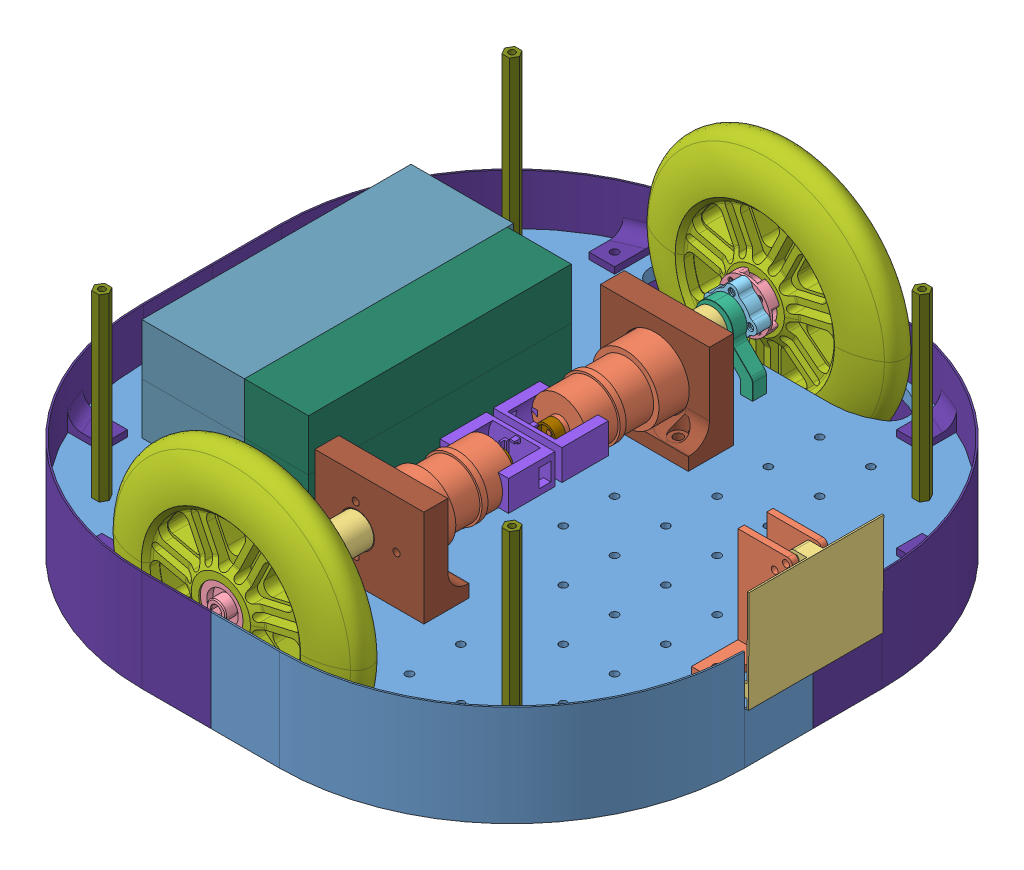
SolidWorks assembly BasePlateAssembly, configuration Default. Lengths in mm.
Overall size (300.06 127.13 298.45).
46 component instances, 22 part files, 59 mates.
Components (placement in the parent):
- BasePlate-1: BasePlate [Default] at (0 276.6946 0) size (296.86 6.35 296.86)
- DriveBase-1: DriveBase [Default] at (21.7349 245.9728 -86.9216) size (124.46 124.46 293.2)
  - DriveAssemblyLeft-1: DriveAssemblyLeft [Default] at (-13.1108 55.1108 149.3123) size (124.46 124.46 144.88)
    - 1400-0032-0032 assembly.STEP-1: 1400-0032-0032 assembly.STEP [Default] at (6.581 -3.5947 -1.114) size (42.17 43 8) (hidden)
    - Motor-2: Motor [Default] at (-2.6241 5.961 7.9343) x (0 0 -1) z (0 1 0) size (70.6 33 33)
    - Coupler-1: Coupler [Default] at (-8.6241 5.961 25.3343) x (0 0 1) z (-0.88407 -0.467355 0) size (22.5 16 16)
    - 595630 assembly.STEP-1: 595630 assembly.STEP [Default] at (-50.3353 -14.4315 51.5475) x (-0.997959 -0.063851 0) z (-0.063851 0.997959 0) size (25.39 31.39 25.39)
    - 545579 assembly.STEP-1: 545579 assembly.STEP [Default] at (19.7418 -41.3992 66.5368) x (0.750814 -0.660514 0) z (0.660514 0.750814 0) size (20.57 9.61 20.57)
    - 1602-0032-0250 assembly.STEP-1: 1602-0032-0250 assembly.STEP [Default] at (-40.6325 25.9608 25.7882) x (-1 0 0) z (0 -1 0) size (38 7 33.35)
    - 3608-0001-0125 assembly.STEP-1: 3608-0001-0125 assembly.STEP [Default] at (-21.1121 15.7426 69.8072) size (124.46 124.46 23.93)
    - Encoder_BracketMount_V2-1: Encoder_BracketMount_V2 [Default] at (-2.6241 5.961 -58.6657) x (0 1 0) z (0 0 1) size (15 34 23)
    - Encoder_MagnetMount_V2-1: Encoder_MagnetMount_V2 [Default] at (-2.6241 5.961 -49.8657) x (-1 0 0) z (0 0 -1) size (10 10 5)
    - 634060-1: 634060 [Default] at (-8.6241 5.961 55.6343) x (0 -1 0) z (1 0 0) size (5.71 25.4 6.34)
    - MotorMount-1: MotorMount [Default] at (-2.6241 5.961 11.1093) size (54 48 23.2)
  - DriveAssemblyRight-1: DriveAssemblyRight [Default] at (-18.359 55.1108 24.531) x (-1 0 0) z (0 0 -1) size (124.46 124.46 144.88)
    - 1400-0032-0032 assembly.STEP-1: 1400-0032-0032 assembly.STEP [Default] at (6.581 -3.5947 -1.114) size (42.17 43 8) (hidden)
    - Motor-2: Motor [Default] at (-2.6241 5.961 7.9343) x (0 0 -1) z (0 -1 0) size (70.6 33 33)
    - Coupler-1: Coupler [Default] at (3.3759 5.961 25.3343) x (0 0 1) z (-0.88407 -0.467355 0) size (22.5 16 16)
    - 595630 assembly.STEP-1: 595630 assembly.STEP [Default] at (-38.3353 -14.4315 51.5475) x (-0.997959 -0.063851 0) z (-0.063851 0.997959 0) size (25.39 31.39 25.39)
    - 545579 assembly.STEP-1: 545579 assembly.STEP [Default] at (31.7418 -41.3992 66.5368) x (0.750814 -0.660514 0) z (0.660514 0.750814 0) size (20.57 9.61 20.57)
    - 1602-0032-0250 assembly.STEP-1: 1602-0032-0250 assembly.STEP [Default] at (-28.6325 25.9608 25.7882) x (-1 0 0) z (0 -1 0) size (38 7 33.35)
    - 3608-0001-0125 assembly.STEP-1: 3608-0001-0125 assembly.STEP [Default] at (-9.1121 15.7426 69.8072) size (124.46 124.46 23.93)
    - Encoder_BracketMount_V2-1: Encoder_BracketMount_V2 [Default] at (-2.6241 5.961 -58.6657) x (0 1 0) z (0 0 1) size (15 34 23)
    - Encoder_MagnetMount_V2-1: Encoder_MagnetMount_V2 [Default] at (-2.6241 5.961 -49.8657) x (-1 0 0) z (0 0 -1) size (10 10 5)
    - 634060-1: 634060 [Default] at (3.3759 5.961 55.6343) x (0 -1 0) z (1 0 0) size (5.71 25.4 6.34)
    - MotorMount-1: MotorMount [Default] at (-2.6241 5.961 11.1093) size (54 48 23.2)
- pololu-ball-caster-with-0-750in-metal-ball.step-1: pololu-ball-caster-with-0-750in-metal-ball.step [Default] at (-127 266.2445 0) x (0 0 -1) z (-1 0 0) size (22.87 20.95 22.86)
- pololu-ball-caster-with-0-750in-metal-ball.step-2: pololu-ball-caster-with-0-750in-metal-ball.step [Default] at (127 266.2445 0) x (-0.088505 0 -0.996076) z (-0.996076 0 0.088505) size (22.87 20.95 22.86)
- CasterMount-1: CasterMount [Default] at (127 272.023 0) x (-1 0 0) z (0 0 1) size (22.86 10.45 63.5)
- CasterMount-2: CasterMount [Default] at (-127 272.023 0) x (-1 0 0) z (0 0 1) size (22.86 10.45 63.5)
- NiMH Battery-2: NiMH Battery [Default] at (-91.2812 308.4446 0) x (0 0 -1) z (1 0 0) size (133.35 25.4 50.8)
- NiMH Battery-3: NiMH Battery [Default] at (-91.2812 283.0446 0) x (0 0 -1) z (1 0 0) size (133.35 25.4 50.8)
- 5V Battery-2: 5V Battery [Default] at (-50.0063 283.0446 1.5875) x (0 0 -1) z (1 0 0) size (130.18 25.4 31.75)
- 5V Battery-3: 5V Battery [Default] at (-50.0063 308.4446 1.5875) x (0 0 -1) z (1 0 0) size (130.18 25.4 31.75)
- Standoff-1: Standoff [Default] at (101.6 283.0446 -101.6) size (7.33 88.9 6.35)
- Standoff-2: Standoff [Default] at (101.6 283.0446 101.6) size (7.33 88.9 6.35)
- Standoff-3: Standoff [Default] at (-101.6 283.0446 101.6) size (7.33 88.9 6.35)
- Standoff-4: Standoff [Default] at (-101.6 283.0446 -101.6) size (7.33 88.9 6.35)
- BumperMountsV2-1: BumperMountsV2 [Default] at (0 276.6946 0) size (149.22 50 149.22)
- tapesensormount-1: tapesensormount [Default] at (6 274.1946 60.325) size (44.45 25.15 14.08)
- tapesensormount-2: tapesensormount [Default] at (6 274.1946 -60.325) x (-1 0 0) z (0 0 -1) size (44.45 25.15 14.08)
- BumperMountsV2-2: BumperMountsV2 [Default] at (0 276.6946 0) x (0 0 -1) z (1 0 0) size (149.22 50 149.22)
- BumperMountsLimitV2-1: BumperMountsLimitV2 [Default] at (0 276.6946 0) x (-1 0 0) z (0 0 -1) size (149.22 50 149.22)
- BumperMountsV2-3: BumperMountsV2 [Default] at (0 276.6946 0) x (0 0 1) z (-1 0 0) size (149.22 50 149.22)
- limitswitchmount-1: limitswitchmount [Default] at (127 283.0446 0) x (0 0 1) z (-1 0 0) size (63.5 50.8 27.78)
- limitplate-1: limitplate [Default] at (149.8442 308.4017 0) x (0 0 -1) z (0.999969 -0.007846 0) size (66.67 50.8 9.52)
Mates (geometry in assembly coordinates):
- Coincident1: coincident anti-aligned: plane of BasePlate-1 through (-34.1313 283.0446 34.1313) normal (0 1 0); plane of DriveBase-1/DriveAssemblyRight-1/1400-0032-0032 assembly.STEP-1 through (-7 283.0446 -64.325) normal (0 -1 0)
- Symmetric1: symmetric: plane of BasePlate-1 through (0 276.6946 0) normal (0 0 1); plane of DriveBase-1/DriveAssemblyLeft-1/1400-0032-0032 assembly.STEP-1 through (6 307.0446 -56.325) normal (0 0 1); plane of DriveBase-1/DriveAssemblyRight-1/1400-0032-0032 assembly.STEP-1 through (6 307.0446 56.325) normal (0 0 -1)
- Symmetric2: symmetric aligned: plane of BasePlate-1 through (0 276.6946 0) normal (1 0 0); plane of DriveBase-1/DriveAssemblyLeft-1/1602-0032-0250 assembly.STEP-1 through (-19 292.2872 100.1875) normal (-1 0 0); plane of DriveBase-1/DriveAssemblyLeft-1/1602-0032-0250 assembly.STEP-1 through (19 292.2872 100.1875) normal (1 0 0)
- Concentric4: concentric anti-aligned: cylinder of pololu-ball-caster-with-0-750in-metal-ball.step-2 through (127 262.4345 0) axis (0 -1 0) radius 11.43; cylinder of CasterMount-1 through (127 266.2445 0) axis (0 1 0) radius 11.43
- Coincident5: coincident anti-aligned: plane of pololu-ball-caster-with-0-750in-metal-ball.step-2 through (127 266.2445 0) normal (0 1 0); plane of CasterMount-1 through (127 266.2445 0) normal (0 -1 0)
- Concentric8: concentric anti-aligned: cylinder of pololu-ball-caster-with-0-750in-metal-ball.step-1 through (-127 262.4345 0) axis (0 -1 0) radius 11.43; cylinder of CasterMount-2 through (-127 266.2445 0) axis (0 1 0) radius 11.43
- Coincident6: coincident anti-aligned: plane of pololu-ball-caster-with-0-750in-metal-ball.step-1 through (-127 266.2445 0) normal (0 1 0); plane of CasterMount-2 through (-127 266.2445 0) normal (0 -1 0)
- Coincident12: coincident aligned: plane of BasePlate-1 through (0 276.6946 0) normal (0 0 1)
- Coincident14: coincident aligned: plane of BasePlate-1 through (0 276.6946 0) normal (1 0 0)
- Coincident16: coincident anti-aligned: plane of NiMH Battery-2 through (-91.2812 308.4446 0) normal (0 -1 0); plane of NiMH Battery-3 through (-91.2812 308.4446 0) normal (0 1 0)
- Coincident17: coincident aligned: plane of NiMH Battery-2 through (-65.8813 333.8446 66.675) normal (1 0 0); plane of NiMH Battery-3 through (-65.8813 308.4446 66.675) normal (1 0 0)
- Coincident18: coincident aligned: plane of NiMH Battery-2 through (-65.8813 333.8446 66.675) normal (0 0 1); plane of NiMH Battery-3 through (-65.8813 308.4446 66.675) normal (0 0 1)
- Coincident19: coincident aligned: plane of NiMH Battery-2 through (-65.8813 333.8446 66.675) normal (0 0 1); plane of 5V Battery-3 through (-34.1313 333.8446 66.675) normal (0 0 1)
- Coincident20: coincident aligned: plane of NiMH Battery-2 through (-91.2812 333.8446 0) normal (0 1 0); plane of 5V Battery-3 through (-50.0063 333.8446 1.5875) normal (0 1 0)
- Coincident21: coincident anti-aligned: plane of 5V Battery-2 through (-50.0063 308.4446 1.5875) normal (0 1 0); plane of 5V Battery-3 through (-50.0063 308.4446 1.5875) normal (0 -1 0)
- Coincident22: coincident anti-aligned: plane of NiMH Battery-3 through (-65.8813 308.4446 66.675) normal (1 0 0); plane of 5V Battery-2 through (-65.8813 308.4446 66.675) normal (-1 0 0)
- Coincident23: coincident aligned: plane of 5V Battery-2 through (-34.1313 308.4446 66.675) normal (1 0 0); plane of 5V Battery-3 through (-34.1313 333.8446 66.675) normal (1 0 0)
- Coincident24: coincident aligned: plane of NiMH Battery-3 through (-65.8813 308.4446 66.675) normal (0 0 1); plane of 5V Battery-3 through (-34.1313 333.8446 66.675) normal (0 0 1)
- Coincident25: coincident aligned: plane of 5V Battery-2 through (-34.1313 308.4446 66.675) normal (0 0 1); plane of 5V Battery-3 through (-34.1313 333.8446 66.675) normal (0 0 1)
- Coincident26: coincident anti-aligned: plane of BasePlate-1 through (-34.1313 283.0446 34.1313) normal (0 1 0); plane of NiMH Battery-3 through (-91.2812 283.0446 0) normal (0 -1 0)
- Width1: width aligned: plane of NiMH Battery-2 through (-65.8813 333.8446 66.675) normal (0 0 1); plane of NiMH Battery-2 through (-65.8813 333.8446 -66.675) normal (0 0 -1); plane of BasePlate-1 through (-34.1313 283.0446 148.4312) normal (0 0 1); plane of BasePlate-1 through (-34.1313 283.0446 -148.4312) normal (0 0 -1)
- Distance4: distance = 31.75 mm aligned: plane of NiMH Battery-3 through (-116.6813 308.4446 66.675) normal (-1 0 0); plane of BasePlate-1 through (-148.4312 283.0446 34.1313) normal (-1 0 0)
- Concentric13: concentric aligned: cylinder of BasePlate-1 through (127 283.0446 25.4) axis (0 1 0) radius 1.8986; cylinder of CasterMount-1 through (127 276.6946 25.4) axis (0 1 0) radius 1.8986
- Concentric14: concentric aligned: cylinder of BasePlate-1 through (127 283.0446 -25.4) axis (0 1 0) radius 1.8986; cylinder of CasterMount-1 through (127 276.6946 -25.4) axis (0 1 0) radius 1.8986
- Concentric15: concentric aligned: cylinder of BasePlate-1 through (-127 283.0446 25.4) axis (0 1 0) radius 1.8986; cylinder of CasterMount-2 through (-127 276.6946 25.4) axis (0 1 0) radius 1.8986
- Concentric16: concentric aligned: cylinder of BasePlate-1 through (-127 283.0446 -25.4) axis (0 1 0) radius 1.8986; cylinder of CasterMount-2 through (-127 276.6946 -25.4) axis (0 1 0) radius 1.8986
- Coincident36: coincident anti-aligned: plane of BasePlate-1 through (-34.1313 276.6946 34.1313) normal (0 -1 0); plane of CasterMount-1 through (127 276.6946 0) normal (0 1 0)
- Coincident37: coincident anti-aligned: plane of BasePlate-1 through (-34.1313 276.6946 34.1313) normal (0 -1 0); plane of CasterMount-2 through (-127 276.6946 0) normal (0 1 0)
- Concentric21: concentric anti-aligned: cylinder of Standoff-1 through (101.6 371.9446 -101.6) axis (0 -1 0) radius 1.5875; cylinder of BasePlate-1 through (101.6 283.0446 -101.6) axis (0 1 0) radius 1.8986
- Concentric22: concentric anti-aligned: cylinder of BasePlate-1 through (101.6 283.0446 101.6) axis (0 1 0) radius 1.8986; cylinder of Standoff-2 through (101.6 371.9446 101.6) axis (0 -1 0) radius 1.5875
- Concentric23: concentric anti-aligned: cylinder of BasePlate-1 through (-101.6 283.0446 101.6) axis (0 1 0) radius 1.8986; cylinder of Standoff-3 through (-101.6 371.9446 101.6) axis (0 -1 0) radius 1.5875
- Concentric24: concentric anti-aligned: cylinder of BasePlate-1 through (-101.6 283.0446 -101.6) axis (0 1 0) radius 1.8986; cylinder of Standoff-4 through (-101.6 371.9446 -101.6) axis (0 -1 0) radius 1.5875
- Coincident40: coincident anti-aligned: plane of BasePlate-1 through (-34.1313 283.0446 34.1313) normal (0 1 0); plane of Standoff-4 through (-101.6 283.0446 -101.6) normal (0 -1 0)
- Coincident41: coincident anti-aligned: plane of BasePlate-1 through (-34.1313 283.0446 34.1313) normal (0 1 0); plane of Standoff-1 through (101.6 283.0446 -101.6) normal (0 -1 0)
- Coincident42: coincident anti-aligned: plane of BasePlate-1 through (-34.1313 283.0446 34.1313) normal (0 1 0); plane of Standoff-3 through (-101.6 283.0446 101.6) normal (0 -1 0)
- Coincident43: coincident anti-aligned: plane of BasePlate-1 through (-34.1313 283.0446 34.1313) normal (0 1 0); plane of Standoff-2 through (101.6 283.0446 101.6) normal (0 -1 0)
- Concentric25: concentric aligned: cylinder of BasePlate-1 through (-127 283.0446 -76.2) axis (0 1 0) radius 1.8986; cylinder of BumperMountsV2-1 through (-127 283.0446 -76.2) axis (0 1 0) radius 1.8986
- Concentric26: concentric aligned: cylinder of BasePlate-1 through (-76.2 283.0446 -127) axis (0 1 0) radius 1.8986; cylinder of BumperMountsV2-1 through (-76.2 283.0446 -127) axis (0 1 0) radius 1.8986
- Coincident44: coincident anti-aligned: plane of BasePlate-1 through (-34.1313 283.0446 34.1313) normal (0 1 0); plane of BumperMountsV2-1 through (-34.1313 283.0446 34.1313) normal (0 -1 0)
- Concentric27: concentric anti-aligned: cylinder of BasePlate-1 through (22 283.0446 60.325) axis (0 1 0) radius 2.25; cylinder of tapesensormount-1 through (22 276.6946 60.325) axis (0 -1 0) radius 2.25
- Concentric28: concentric anti-aligned: cylinder of BasePlate-1 through (-10 283.0446 60.325) axis (0 1 0) radius 2.25; cylinder of tapesensormount-1 through (-10 276.6946 60.325) axis (0 -1 0) radius 2.25
- Coincident45: coincident anti-aligned: plane of BasePlate-1 through (-34.1313 276.6946 34.1313) normal (0 -1 0); plane of tapesensormount-1 through (6 276.6946 60.325) normal (0 1 0)
- Concentric29: concentric anti-aligned: cylinder of BasePlate-1 through (22 283.0446 -60.325) axis (0 1 0) radius 2.25; cylinder of tapesensormount-2 through (22 276.6946 -60.325) axis (0 -1 0) radius 2.25
- Concentric30: concentric anti-aligned: cylinder of DriveBase-1/DriveAssemblyRight-1/MotorMount-1 through (-10 289.3946 -60.325) axis (0 1 0) radius 2.25; cylinder of tapesensormount-2 through (-10 276.6946 -60.325) axis (0 -1 0) radius 2.25
- Coincident46: coincident anti-aligned: plane of BasePlate-1 through (-34.1313 276.6946 34.1313) normal (0 -1 0); plane of tapesensormount-2 through (6 276.6946 -60.325) normal (0 1 0)
- Concentric31: concentric aligned: cylinder of BasePlate-1 through (76.2 283.0446 -127) axis (0 1 0) radius 1.8986; cylinder of BumperMountsV2-3 through (76.2 283.0446 -127) axis (0 1 0) radius 1.8986
- Concentric32: concentric aligned: cylinder of BasePlate-1 through (127 283.0446 -76.2) axis (0 1 0) radius 1.8986; cylinder of BumperMountsV2-3 through (127 283.0446 -76.2) axis (0 1 0) radius 1.8986
- Concentric33: concentric aligned: cylinder of BasePlate-1 through (127 283.0446 76.2) axis (0 1 0) radius 1.8986; cylinder of BumperMountsLimitV2-1 through (127 283.0446 76.2) axis (0 1 0) radius 1.8986
- Concentric34: concentric aligned: cylinder of BasePlate-1 through (76.2 283.0446 127) axis (0 1 0) radius 1.8986; cylinder of BumperMountsLimitV2-1 through (76.2 283.0446 127) axis (0 1 0) radius 1.8986
- Concentric35: concentric aligned: cylinder of BasePlate-1 through (-127 283.0446 76.2) axis (0 1 0) radius 1.8986; cylinder of BumperMountsV2-2 through (-127 283.0446 76.2) axis (0 1 0) radius 1.8986
- Concentric36: concentric aligned: cylinder of BasePlate-1 through (-76.2 283.0446 127) axis (0 1 0) radius 1.8986; cylinder of BumperMountsV2-2 through (-76.2 283.0446 127) axis (0 1 0) radius 1.8986
- Coincident47: coincident aligned: plane of BumperMountsV2-1 through (0 308.0446 0) normal (0 1 0); plane of BumperMountsV2-3 through (0 308.0446 0) normal (0 1 0)
- Coincident48: coincident aligned: plane of BumperMountsLimitV2-1 through (0 308.0446 0) normal (0 1 0); plane of BumperMountsV2-3 through (0 308.0446 0) normal (0 1 0)
- Coincident49: coincident aligned: plane of BumperMountsV2-1 through (0 308.0446 0) normal (0 1 0); plane of BumperMountsV2-2 through (0 308.0446 0) normal (0 1 0)
- Concentric37: concentric anti-aligned: cylinder of BasePlate-1 through (127 283.0446 25.4) axis (0 1 0) radius 1.8986; cylinder of limitswitchmount-1 through (127 283.0446 25.4) axis (0 -1 0) radius 1.8986
- Concentric38: concentric anti-aligned: cylinder of BasePlate-1 through (127 283.0446 -25.4) axis (0 1 0) radius 1.8986; cylinder of limitswitchmount-1 through (127 283.0446 -25.4) axis (0 -1 0) radius 1.8986
- Coincident50: coincident anti-aligned: plane of BasePlate-1 through (-34.1313 283.0446 34.1313) normal (0 1 0); plane of limitswitchmount-1 through (127 283.0446 0) normal (0 -1 0)
- Concentric39: concentric aligned: cylinder of limitswitchmount-1 through (144.4625 330.6696 -8.7312) axis (0 0 -1) radius 1.7; cylinder of limitplate-1 through (144.4625 330.6696 0) axis (0 0 -1) radius 1.7
- Width2: width anti-aligned: plane of limitswitchmount-1 through (120.65 327.4946 -5.5563) normal (0 0 1); plane of limitswitchmount-1 through (120.65 327.4946 5.5563) normal (0 0 -1); plane of limitplate-1 through (150.4386 282.9962 -33.3375) normal (0 0 -1); plane of limitplate-1 through (150.4386 282.9962 33.3375) normal (0 0 1)
